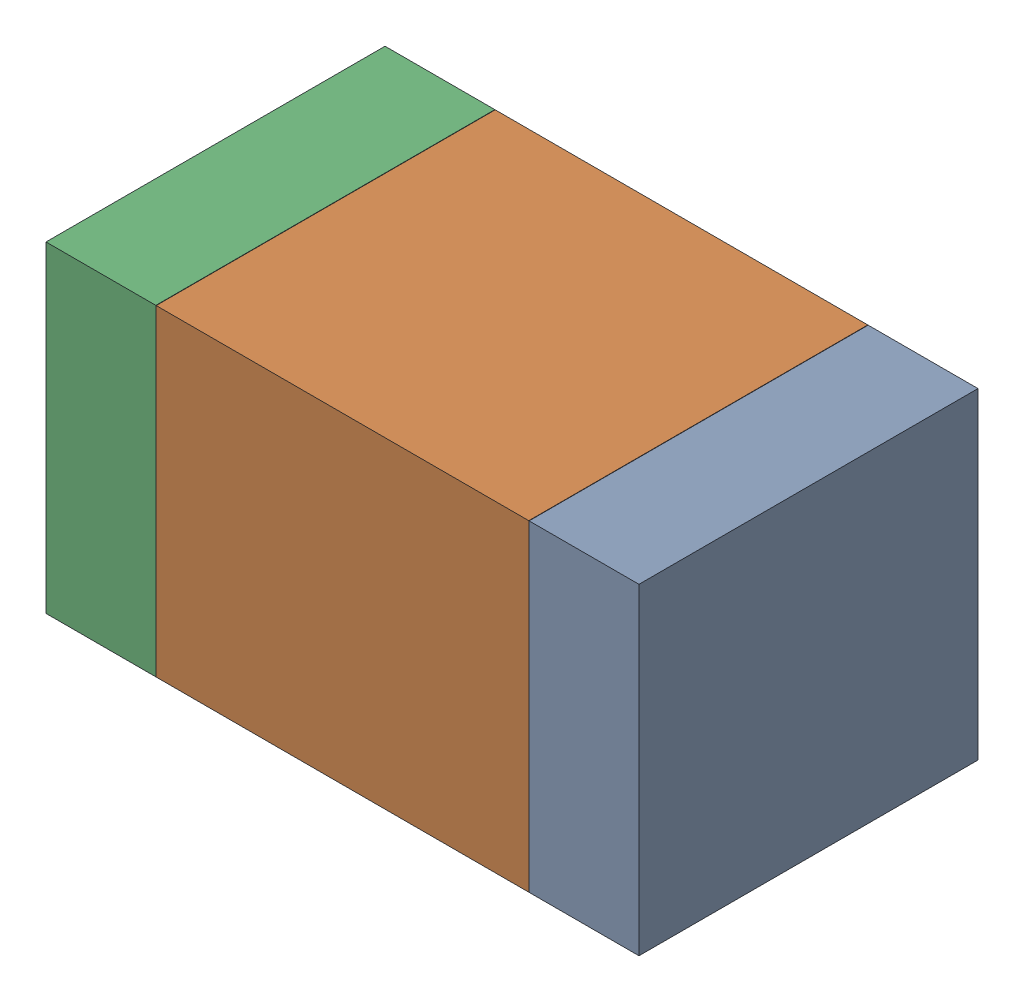
SolidWorks assembly C12, configuration Default. Lengths in mm.
Overall size (1.75 0.95 1).
6 component instances, 2 part files, 0 mates.
Components (placement in the parent):
- 6575498272-1: 6575498272 [Default] at (26.3665 25.908 0) size (0.32 0.95 1)
  - Extruded_8-1: Extruded_8 [Default] at origin size (0.32 0.95 1)
- 6575498112-1: 6575498112 [Default] at (25.654 25.908 0) size (1.1 0.95 1)
  - Extruded_9-1: Extruded_9 [Default] at origin size (1.1 0.95 1)
- 6575498272-2: 6575498272 [Default] at (24.9415 25.908 0) size (0.32 0.95 1)
  - Extruded_8-1: Extruded_8 [Default] at origin size (0.32 0.95 1)
